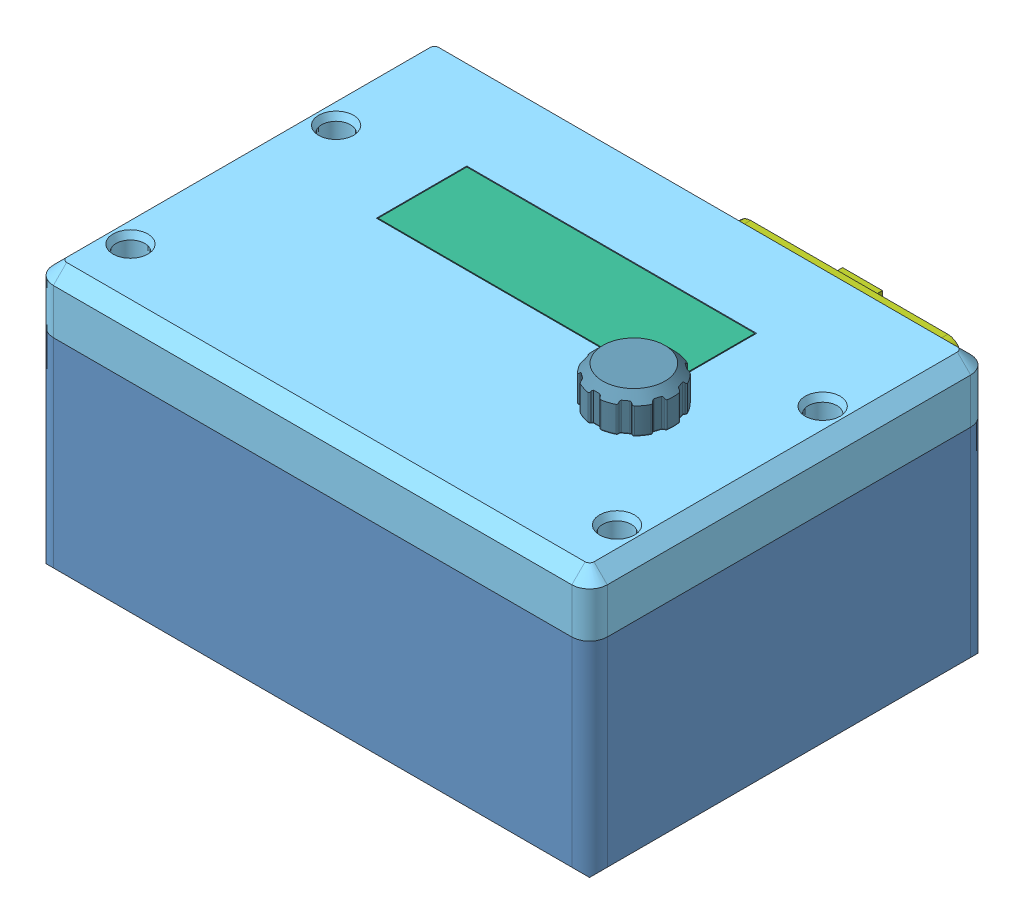
SolidWorks assembly Timer, configuration Standard. Lengths in mm.
Overall size (125 70 99.1).
33 component instances, 15 part files, 42 mates.
Components (placement in the parent):
- Timer-Gehaeuse_unten-1: Timer-Gehaeuse_unten [Standard] at origin size (125 52.22 90)
- Platine_Timer-1: Platine_Timer [Standard] at (0 42 8) size (100 21.5 66)
- Trafo_6V-1: Trafo_6V [Standard] at (30.6 1.6 23.75) size (32.4 24 27.3)
- Kaltgeraete_Einbaubuchse_Sicherung-1: Kaltgeraete_Einbaubuchse_Sicherung [Standard] at (-33.7 23.5 -45) x (-1 0 0) z (0 0 1) size (44.5 34 23)
- Timer-Gehaeuse_oben-1: Timer-Gehaeuse_oben [Standard] at (0 48 0) size (125 21.9 90)
- Scheibe-1: Scheibe [Standard] at (0.5 61.2 -11.8) x (-1 0 0) z (0 0 1) size (65 3 20)
- Schuko-Einbaubuchse-1: Schuko-Einbaubuchse [Standard] at (25 28.25 -45) x (-1 0 0) z (0 0 -1) size (50.5 50.5 37.1)
- CIRCUIT BOARD,TEENSY LC.step-1: CIRCUIT BOARD,TEENSY LC.step [Standard] at (-24.145 55.1 8.5) x (1 0 0) z (0 1 0) size (36.86 17.78 4.4)
- Gewindeeinsatz_Messing_offen-1: Gewindeeinsatz_Messing_offen [M3] at (54.9 39.4 -15.2) size (4.19 4 4.17)
- DIN 912 M3 x 10 --- 10N-1: DIN 912 M3 x 10 --- 10N [DIN 912 M3 x 10 --- 10N] at (54.9 52.8 -15.2) x (0 -1 0) z (0 0 -1) size (13 5.5 5.5)
- DIN 912 M3 x 10 --- 10N-2: DIN 912 M3 x 10 --- 10N [DIN 912 M3 x 10 --- 10N] at (-54.9 52.8 31.2) x (0 -1 0) z (0 0 -1) size (13 5.5 5.5)
- DIN 912 M3 x 10 --- 10N-3: DIN 912 M3 x 10 --- 10N [DIN 912 M3 x 10 --- 10N] at (-54.9 52.8 -15.2) x (0 -1 0) z (0 0 -1) size (13 5.5 5.5)
- DIN 912 M3 x 10 --- 10N-4: DIN 912 M3 x 10 --- 10N [DIN 912 M3 x 10 --- 10N] at (54.9 52.8 31.2) x (0 -1 0) z (0 0 -1) size (13 5.5 5.5)
- Gewindeeinsatz_Messing_offen-2: Gewindeeinsatz_Messing_offen [M3] at (-54.9 39.4 31.2) size (4.19 4 4.17)
- Gewindeeinsatz_Messing_offen-3: Gewindeeinsatz_Messing_offen [M3] at (-54.9 39.4 -15.2) size (4.19 4 4.17)
- Gewindeeinsatz_Messing_offen-4: Gewindeeinsatz_Messing_offen [M3] at (54.9 39.4 31.2) size (4.19 4 4.17)
- SSR-2A-Modul-1: SSR-2A-Modul [Standard] at (-25 6.1 20) x (0 0 -1) z (1 0 0) size (25 21.5 34)
- Hexagon Thin Nut ISO 4035 - M3 - N-1: Hexagon Thin Nut ISO 4035 - M3 - N [Hexagon Thin Nut ISO 4035 - M3 - N] at (-15.7 23.5 -41.6) size (5.5 6.35 1.8)
- Hexagon Thin Nut ISO 4035 - M3 - N-2: Hexagon Thin Nut ISO 4035 - M3 - N [Hexagon Thin Nut ISO 4035 - M3 - N] at (6 9.25 -41.6) size (5.5 6.35 1.8)
- DIN 7991 - M3 x 8 --- 4.8N-1: DIN 7991 - M3 x 8 --- 4.8N [DIN 7991 - M3 x 8 --- 4.8N] at (6 9.25 -51.1) x (0 0 1) z (1 0 0) size (8 5.7 5.7)
- DIN 7991 - M3 x 8 --- 4.8N-2: DIN 7991 - M3 x 8 --- 4.8N [DIN 7991 - M3 x 8 --- 4.8N] at (-15.7 23.5 -48) x (0 0 1) z (-0.923728 -0.383049 0) size (8 5.7 5.7)
- Hexagon Thin Nut ISO 4035 - M3 - N-3: Hexagon Thin Nut ISO 4035 - M3 - N [Hexagon Thin Nut ISO 4035 - M3 - N] at (-51.7 23.5 -41.6) size (5.5 6.35 1.8)
- DIN 7991 - M3 x 8 --- 4.8N-3: DIN 7991 - M3 x 8 --- 4.8N [DIN 7991 - M3 x 8 --- 4.8N] at (-51.7 23.5 -48) x (0 0 1) z (-0.923728 -0.383049 0) size (8 5.7 5.7)
- Hexagon Thin Nut ISO 4035 - M3 - N-4: Hexagon Thin Nut ISO 4035 - M3 - N [Hexagon Thin Nut ISO 4035 - M3 - N] at (6 47.25 -41.6) size (5.5 6.35 1.8)
- Hexagon Thin Nut ISO 4035 - M3 - N-5: Hexagon Thin Nut ISO 4035 - M3 - N [Hexagon Thin Nut ISO 4035 - M3 - N] at (44 47.25 -41.6) size (5.5 6.35 1.8)
- Hexagon Thin Nut ISO 4035 - M3 - N-6: Hexagon Thin Nut ISO 4035 - M3 - N [Hexagon Thin Nut ISO 4035 - M3 - N] at (44 9.25 -41.6) size (5.5 6.35 1.8)
- DIN 7991 - M3 x 8 --- 4.8N-4: DIN 7991 - M3 x 8 --- 4.8N [DIN 7991 - M3 x 8 --- 4.8N] at (6 47.25 -51.1) x (0 0 1) z (1 0 0) size (8 5.7 5.7)
- DIN 7991 - M3 x 8 --- 4.8N-5: DIN 7991 - M3 x 8 --- 4.8N [DIN 7991 - M3 x 8 --- 4.8N] at (44 47.25 -51.1) x (0 0 1) z (1 0 0) size (8 5.7 5.7)
- DIN 7991 - M3 x 8 --- 4.8N-6: DIN 7991 - M3 x 8 --- 4.8N [DIN 7991 - M3 x 8 --- 4.8N] at (44 9.25 -51.1) x (0 0 1) z (1 0 0) size (8 5.7 5.7)
- Drehknopf-1: Drehknopf [Standard] at (34 62 6.5) size (18 13 17.77)
- DIN 912 M3 x 8 --- 8N-1: DIN 912 M3 x 8 --- 8N [DIN 912 M3 x 8 --- 8N] at (-46 46.5 35.4008) x (0 -1 0) z (-0.546944 0 0.837169) size (11 5.5 5.5)
- DIN 912 M3 x 8 --- 8N-2: DIN 912 M3 x 8 --- 8N [DIN 912 M3 x 8 --- 8N] at (46 46.5 -19.4008) x (0 -1 0) z (-0.546944 0 0.837169) size (11 5.5 5.5)
- DIN 912 M3 x 8 --- 8N-3: DIN 912 M3 x 8 --- 8N [DIN 912 M3 x 8 --- 8N] at (-46 46.5 -19.4008) x (0 -1 0) z (-0.546944 0 0.837169) size (11 5.5 5.5)
Mates (geometry in assembly coordinates):
- Deckungsgleich1: coincident anti-aligned: plane of Timer-Gehaeuse_unten-1 through (0 42 16) normal (0 1 0); plane of Platine_Timer-1 through (0 42 8) normal (0 -1 0)
- Abstand2: distance = 8 mm aligned: plane of Platine_Timer-1 through (0 42 8) normal (0 0 1); plane of assembly through (0 0 0) normal (0 0 1)
- Deckungsgleich3: coincident aligned: plane of Platine_Timer-1 through (0 42 8) normal (1 0 0); plane of assembly through (0 0 0) normal (1 0 0)
- Deckungsgleich4: coincident anti-aligned: plane of Timer-Gehaeuse_unten-1 through (0 1.6 0) normal (0 1 0); plane of Trafo_6V-1 through (30.6 1.6 23.75) normal (0 -1 0)
- Deckungsgleich5: coincident anti-aligned: plane of Timer-Gehaeuse_unten-1 through (14.4 17.6 22.45) normal (1 0 0); plane of Trafo_6V-1 through (14.4 25.6 37.4) normal (-1 0 0)
- Deckungsgleich6: coincident anti-aligned: plane of Timer-Gehaeuse_unten-1 through (19.25 17.6 37.4) normal (0 0 -1); plane of Trafo_6V-1 through (14.4 25.6 37.4) normal (0 0 1)
- Deckungsgleich7: coincident anti-aligned: plane of Timer-Gehaeuse_unten-1 through (-62.5 48 -45) normal (0 0 -1); plane of Kaltgeraete_Einbaubuchse_Sicherung-1 through (-33.7 23.5 -45) normal (0 0 1)
- Deckungsgleich8: coincident anti-aligned: plane of Timer-Gehaeuse_unten-1 through (-47.5 8 -45.001) normal (0 1 0); plane of Kaltgeraete_Einbaubuchse_Sicherung-1 through (-20.2 8 -25) normal (0 -1 0)
- Symmetrisch1: symmetric aligned: plane of Timer-Gehaeuse_unten-1 through (-47.5 48 -45.001) normal (1 0 0); plane of Kaltgeraete_Einbaubuchse_Sicherung-1 through (-19.9 48 -45.001) normal (-1 0 0); plane of Timer-Gehaeuse_unten-1 through (-33.7 23.5 -45) normal (-1 0 0)
- Deckungsgleich10: coincident aligned: plane of Timer-Gehaeuse_unten-1 through (0 48 0) normal (0 1 0); plane of Timer-Gehaeuse_oben-1 through (0 48 0) normal (0 1 0)
- Deckungsgleich11: coincident aligned: plane of Timer-Gehaeuse_oben-1 through (0 48 0) normal (1 0 0); plane of assembly through (0 0 0) normal (1 0 0)
- Deckungsgleich12: coincident aligned: plane of Timer-Gehaeuse_oben-1 through (0 48 0) normal (0 0 1); plane of assembly through (0 0 0) normal (0 0 1)
- Deckungsgleich13: coincident aligned: plane of Timer-Gehaeuse_oben-1 through (-58.5 61.2 -41) normal (0 1 0); plane of Scheibe-1 through (0.5 61.2 -11.8) normal (0 1 0)
- Symmetrisch2: symmetric aligned: plane of Timer-Gehaeuse_oben-1 through (-32.2 48 -22) normal (0 0 1); plane of Scheibe-1 through (-32.2 48 -1.6) normal (0 0 -1); plane of Timer-Gehaeuse_oben-1 through (0.5 61.2 -11.8) normal (0 0 1)
- Symmetrisch3: symmetric aligned: plane of Timer-Gehaeuse_oben-1 through (33.2 48 -22) normal (-1 0 0); plane of Scheibe-1 through (-32.2 48 -22) normal (1 0 0); plane of Timer-Gehaeuse_oben-1 through (0.5 61.2 -11.8) normal (-1 0 0)
- Deckungsgleich14: coincident anti-aligned: plane of Timer-Gehaeuse_unten-1 through (-62.5 48 -45) normal (0 0 -1); plane of Schuko-Einbaubuchse-1 through (25 28.25 -45) normal (0 0 1)
- Abstand1: distance = 25 mm anti-aligned: plane of Schuko-Einbaubuchse-1 through (25 28.25 -45) normal (-1 0 0); plane of assembly through (0 0 0) normal (1 0 0)
- Deckungsgleich21: coincident: line of Timer-Gehaeuse_unten-1 through (58.5 3 -45) axis (-1 0 0); plane of Schuko-Einbaubuchse-1 through (50.25 3 -51.1) normal (0 -1 0)
- Deckungsgleich16: coincident anti-aligned: plane of Platine_Timer-1 through (0 53.5 8) normal (0 1 0); plane of CIRCUIT BOARD,TEENSY LC.step-1 through (-24.145 53.5 8.5) normal (0 -1 0)
- Deckungsgleich17: coincident aligned: plane of Platine_Timer-1 through (-42 53.5 -0.5) normal (-1 0 0); plane of CIRCUIT BOARD,TEENSY LC.step-1 through (-42 53.5 -0.39) normal (-1 0 0)
- Symmetrisch4: symmetric aligned: plane of Platine_Timer-1 through (-42 53.5 -0.5) normal (0 0 -1); plane of CIRCUIT BOARD,TEENSY LC.step-1 through (-42 53.5 17.5) normal (0 0 1); plane of Platine_Timer-1 through (-24.145 55.1 8.5) normal (0 0 -1)
- Konzentrisch1: concentric anti-aligned: cylinder of Timer-Gehaeuse_unten-1 through (54.9 43.4 -15.2) axis (0 1 0) radius 1.85; cylinder of Gewindeeinsatz_Messing_offen-1 through (54.9 43.4 -15.2) axis (0 -1 0) radius 1.85
- Deckungsgleich18: coincident aligned: plane of Timer-Gehaeuse_unten-1 through (0 43.4 16) normal (0 1 0); plane of Gewindeeinsatz_Messing_offen-1 through (54.9 43.4 -15.2) normal (0 1 0)
- Konzentrisch2: concentric aligned: cylinder of Gewindeeinsatz_Messing_offen-1 through (54.9 43.4 -15.2) axis (0 1 0) radius 1.25; cylinder of DIN 912 M3 x 10 --- 10N-1 through (54.9 84.55 -15.2) axis (0 1 0) radius 1.5
- Deckungsgleich19: coincident anti-aligned: plane of Timer-Gehaeuse_oben-1 through (56.6 49.8 -15.2) normal (0 1 0); plane of DIN 912 M3 x 10 --- 10N-1 through (52.15 49.8 -15.2) normal (0 -1 0)
- Deckungsgleich20: coincident anti-aligned: plane of Timer-Gehaeuse_unten-1 through (-10.75 6.1 29.75) normal (0 1 0); plane of SSR-2A-Modul-1 through (-25 6.1 20) normal (0 -1 0)
- Abstand3: distance = 20 mm anti-aligned: plane of SSR-2A-Modul-1 through (-25 6.1 20) normal (0 0 -1)
- Abstand4: distance = 25 mm aligned: plane of SSR-2A-Modul-1 through (-25 6.1 20) normal (1 0 0)
- Deckungsgleich22: coincident anti-aligned: plane of Timer-Gehaeuse_unten-1 through (-62.5 48 -43.4) normal (0 0 1); plane of Hexagon Thin Nut ISO 4035 - M3 - N-1 through (-21.2 23.5 -43.4) normal (0 0 -1)
- Konzentrisch3: concentric anti-aligned: cylinder of Timer-Gehaeuse_unten-1 through (-15.7 23.5 -45) axis (0 0 -1) radius 1.7; cylinder of Hexagon Thin Nut ISO 4035 - M3 - N-1 through (-15.7 23.5 -43.4) axis (0 0 1) radius 1.25
- Parallel1: parallel aligned: plane of Hexagon Thin Nut ISO 4035 - M3 - N-1 through (-15.7 23.5 -41.6) normal (1 0 0)
- Konzentrisch4: concentric anti-aligned: cylinder of Timer-Gehaeuse_unten-1 through (6 9.25 -45) axis (0 0 -1) radius 1.7; cylinder of Hexagon Thin Nut ISO 4035 - M3 - N-2 through (6 9.25 -43.4) axis (0 0 1) radius 1.25
- Deckungsgleich23: coincident anti-aligned: plane of Timer-Gehaeuse_unten-1 through (-62.5 48 -43.4) normal (0 0 1); plane of Hexagon Thin Nut ISO 4035 - M3 - N-2 through (0.5 9.25 -43.4) normal (0 0 -1)
- Parallel2: parallel aligned: plane of Hexagon Thin Nut ISO 4035 - M3 - N-2 through (6 9.25 -41.6) normal (1 0 0)
- Konzentrisch5: concentric aligned: cylinder of Timer-Gehaeuse_unten-1 through (-15.7 23.5 -45) axis (0 0 -1) radius 1.7; cylinder of DIN 7991 - M3 x 8 --- 4.8N-2 through (-15.7 23.5 -48) axis (0 0 -1) radius 1.5
- Konzentrisch6: concentric aligned: cylinder of Timer-Gehaeuse_unten-1 through (6 9.25 -45) axis (0 0 -1) radius 1.7; cylinder of DIN 7991 - M3 x 8 --- 4.8N-1 through (6 9.25 -51.1) axis (0 0 -1) radius 1.5
- Deckungsgleich27: coincident: plane of Schuko-Einbaubuchse-1 through (25 28.25 -51.1) normal (0 0 -1); point of DIN 7991 - M3 x 8 --- 4.8N-1
- Deckungsgleich28: coincident: plane of Kaltgeraete_Einbaubuchse_Sicherung-1 through (-33.7 23.5 -48) normal (0 0 -1); point of DIN 7991 - M3 x 8 --- 4.8N-2
- Deckungsgleich29: coincident anti-aligned: plane of Platine_Timer-1 through (34 63.5 6.5) normal (0 1 0); plane of Drehknopf-1 through (34 63.5 6.5) normal (0 -1 0)
- Konzentrisch7: concentric anti-aligned: cylinder of Platine_Timer-1 through (34 63.5 6.5) axis (0 -1 0) radius 3; line of Drehknopf-1 through (34 56.35 6.5) axis (0 1 0)
- Konzentrisch8: concentric aligned: cylinder of Timer-Gehaeuse_unten-1 through (-46 42 35.4008) axis (0 1 0) radius 1.25; cylinder of DIN 912 M3 x 8 --- 8N-1 through (-46 78.25 35.4008) axis (0 1 0) radius 1.5
- Deckungsgleich30: coincident anti-aligned: plane of Platine_Timer-1 through (0 43.5 8) normal (0 1 0); plane of DIN 912 M3 x 8 --- 8N-1 through (-43.6978 43.5 36.9049) normal (0 -1 0)
